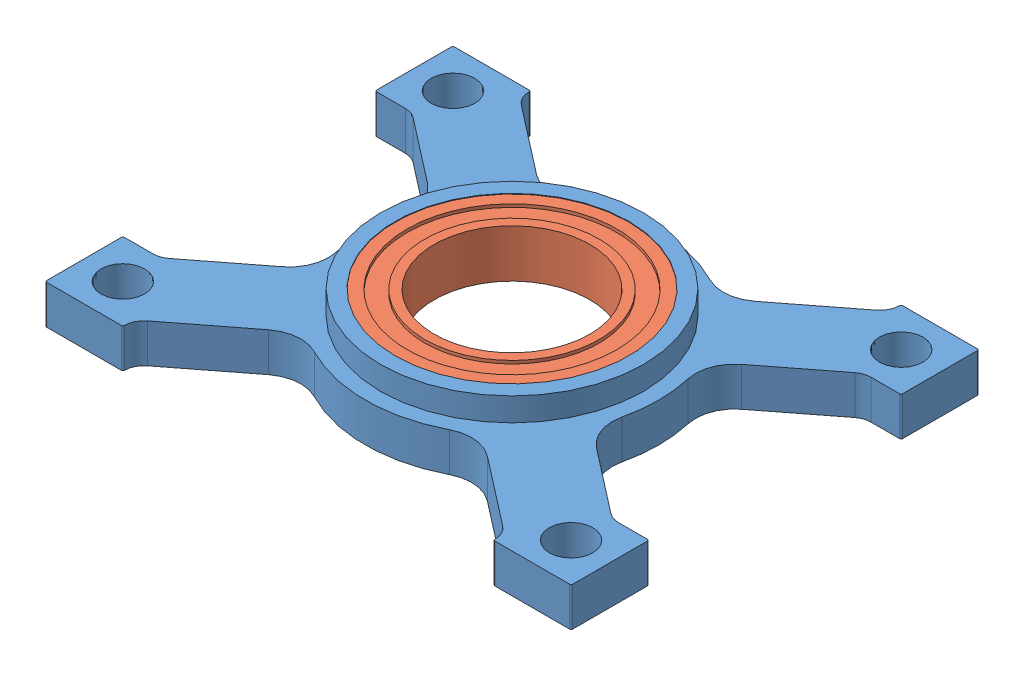
SolidWorks assembly Bearing_mount_subsubass, configuration Default. Lengths in mm.
Overall size (42.93 5.08 33.27).
2 component instances, 2 part files, 0 mates.
Components (placement in the parent):
- 535182-1: 535182 [Default] at (14.2899 18.456 34.8186) size (42.93 5.08 33.27)
- .5 x .75 non flanged bearing-1: .5 x .75 non flanged bearing [Default] at (14.2899 19.5736 34.8186) x (0.770155 0 0.637857) z (-0.637857 0 0.770155) size (19.05 3.91 19.05)
